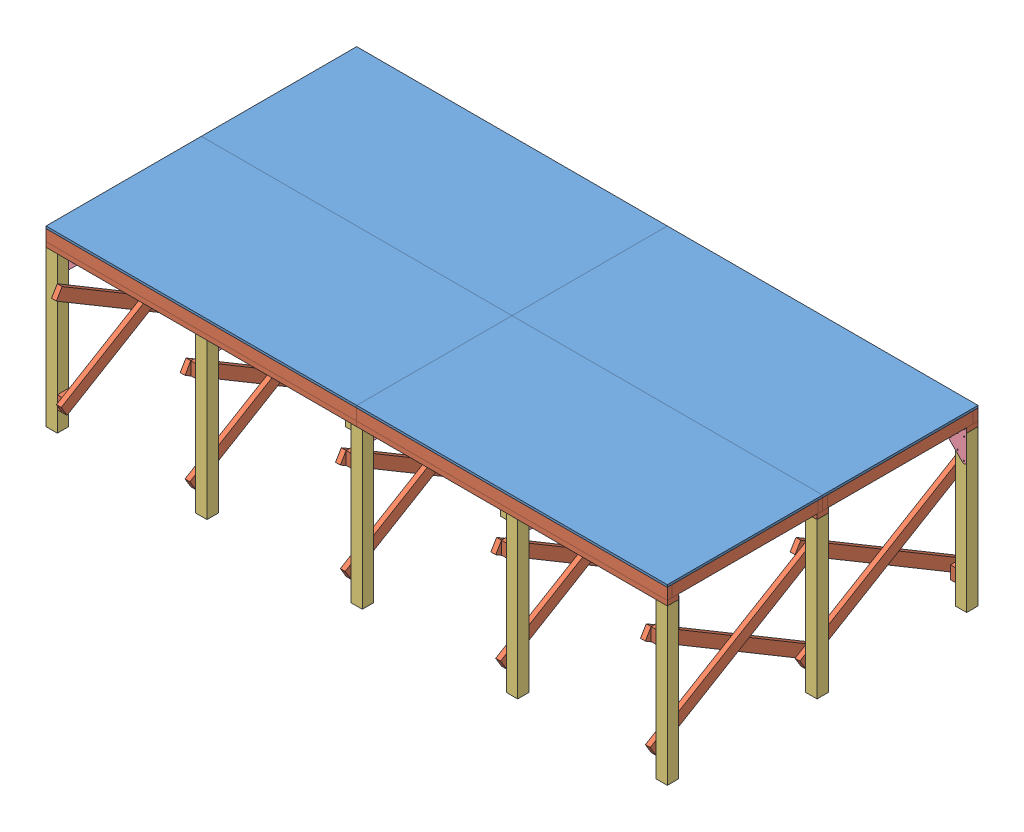
SolidWorks assembly Side Platform, configuration Default. Lengths in mm.
Overall size (5108.48 1373.14 2529.42).
113 component instances, 4 part files, 31 mates.
Components (placement in the parent):
- Platform Top-1: Platform Top [Default] at origin size (2438.4 106.76 1219.2)
  - 4x8-1: 4x8 [Default] at origin size (2438.4 17.86 1219.2)
  - 2x4 Configurable-6: 2x4 Configurable [96" Long] at (0 -53.3781 590.55) x (1 0 0) z (0 0 -1) size (2438.4 88.9 38.1)
  - 2x4 Configurable-7: 2x4 Configurable [96" Long] at (0 -53.3781 -590.55) x (1 0 0) z (0 0 -1) size (2438.4 88.9 38.1)
  - 2x4 Configurable-10: 2x4 Configurable [45" Long] at (-1200.15 -53.3781 0) x (0 0 -1) z (1 0 0) size (1143 88.9 38.1)
  - 2x4 Configurable-11: 2x4 Configurable [45" Long] at (-800.1 -53.3781 0) x (0 0 -1) z (1 0 0) size (1143 88.9 38.1)
  - 2x4 Configurable-12: 2x4 Configurable [45" Long] at (-400.05 -53.3781 0) x (0 0 -1) z (1 0 0) size (1143 88.9 38.1)
  - 2x4 Configurable-13: 2x4 Configurable [45" Long] at (0 -53.3781 0) x (0 0 -1) z (1 0 0) size (1143 88.9 38.1)
  - 2x4 Configurable-14: 2x4 Configurable [45" Long] at (400.05 -53.3781 0) x (0 0 -1) z (1 0 0) size (1143 88.9 38.1)
  - 2x4 Configurable-15: 2x4 Configurable [45" Long] at (800.1 -53.3781 0) x (0 0 -1) z (1 0 0) size (1143 88.9 38.1)
  - 2x4 Configurable-16: 2x4 Configurable [45" Long] at (1200.15 -53.3781 0) x (0 0 -1) z (1 0 0) size (1143 88.9 38.1)
- Platform Top-2: Platform Top [Default] at (-2438.4 0 0) size (2438.4 106.76 1219.2)
  - 4x8-1: 4x8 [Default] at origin size (2438.4 17.86 1219.2)
  - 2x4 Configurable-6: 2x4 Configurable [96" Long] at (0 -53.3781 590.55) x (1 0 0) z (0 0 -1) size (2438.4 88.9 38.1)
  - 2x4 Configurable-7: 2x4 Configurable [96" Long] at (0 -53.3781 -590.55) x (1 0 0) z (0 0 -1) size (2438.4 88.9 38.1)
  - 2x4 Configurable-10: 2x4 Configurable [45" Long] at (-1200.15 -53.3781 0) x (0 0 -1) z (1 0 0) size (1143 88.9 38.1)
  - 2x4 Configurable-11: 2x4 Configurable [45" Long] at (-800.1 -53.3781 0) x (0 0 -1) z (1 0 0) size (1143 88.9 38.1)
  - 2x4 Configurable-12: 2x4 Configurable [45" Long] at (-400.05 -53.3781 0) x (0 0 -1) z (1 0 0) size (1143 88.9 38.1)
  - 2x4 Configurable-13: 2x4 Configurable [45" Long] at (0 -53.3781 0) x (0 0 -1) z (1 0 0) size (1143 88.9 38.1)
  - 2x4 Configurable-14: 2x4 Configurable [45" Long] at (400.05 -53.3781 0) x (0 0 -1) z (1 0 0) size (1143 88.9 38.1)
  - 2x4 Configurable-15: 2x4 Configurable [45" Long] at (800.1 -53.3781 0) x (0 0 -1) z (1 0 0) size (1143 88.9 38.1)
  - 2x4 Configurable-16: 2x4 Configurable [45" Long] at (1200.15 -53.3781 0) x (0 0 -1) z (1 0 0) size (1143 88.9 38.1)
- Platform Top-4: Platform Top [Default] at (0 0 1219.2) size (2438.4 106.76 1219.2)
  - 4x8-1: 4x8 [Default] at origin size (2438.4 17.86 1219.2)
  - 2x4 Configurable-6: 2x4 Configurable [96" Long] at (0 -53.3781 590.55) x (1 0 0) z (0 0 -1) size (2438.4 88.9 38.1)
  - 2x4 Configurable-7: 2x4 Configurable [96" Long] at (0 -53.3781 -590.55) x (1 0 0) z (0 0 -1) size (2438.4 88.9 38.1)
  - 2x4 Configurable-10: 2x4 Configurable [45" Long] at (-1200.15 -53.3781 0) x (0 0 -1) z (1 0 0) size (1143 88.9 38.1)
  - 2x4 Configurable-11: 2x4 Configurable [45" Long] at (-800.1 -53.3781 0) x (0 0 -1) z (1 0 0) size (1143 88.9 38.1)
  - 2x4 Configurable-12: 2x4 Configurable [45" Long] at (-400.05 -53.3781 0) x (0 0 -1) z (1 0 0) size (1143 88.9 38.1)
  - 2x4 Configurable-13: 2x4 Configurable [45" Long] at (0 -53.3781 0) x (0 0 -1) z (1 0 0) size (1143 88.9 38.1)
  - 2x4 Configurable-14: 2x4 Configurable [45" Long] at (400.05 -53.3781 0) x (0 0 -1) z (1 0 0) size (1143 88.9 38.1)
  - 2x4 Configurable-15: 2x4 Configurable [45" Long] at (800.1 -53.3781 0) x (0 0 -1) z (1 0 0) size (1143 88.9 38.1)
  - 2x4 Configurable-16: 2x4 Configurable [45" Long] at (1200.15 -53.3781 0) x (0 0 -1) z (1 0 0) size (1143 88.9 38.1)
- Platform Top-5: Platform Top [Default] at (-2438.4 0 1219.2) size (2438.4 106.76 1219.2)
  - 4x8-1: 4x8 [Default] at origin size (2438.4 17.86 1219.2)
  - 2x4 Configurable-6: 2x4 Configurable [96" Long] at (0 -53.3781 590.55) x (1 0 0) z (0 0 -1) size (2438.4 88.9 38.1)
  - 2x4 Configurable-7: 2x4 Configurable [96" Long] at (0 -53.3781 -590.55) x (1 0 0) z (0 0 -1) size (2438.4 88.9 38.1)
  - 2x4 Configurable-10: 2x4 Configurable [45" Long] at (-1200.15 -53.3781 0) x (0 0 -1) z (1 0 0) size (1143 88.9 38.1)
  - 2x4 Configurable-11: 2x4 Configurable [45" Long] at (-800.1 -53.3781 0) x (0 0 -1) z (1 0 0) size (1143 88.9 38.1)
  - 2x4 Configurable-12: 2x4 Configurable [45" Long] at (-400.05 -53.3781 0) x (0 0 -1) z (1 0 0) size (1143 88.9 38.1)
  - 2x4 Configurable-13: 2x4 Configurable [45" Long] at (0 -53.3781 0) x (0 0 -1) z (1 0 0) size (1143 88.9 38.1)
  - 2x4 Configurable-14: 2x4 Configurable [45" Long] at (400.05 -53.3781 0) x (0 0 -1) z (1 0 0) size (1143 88.9 38.1)
  - 2x4 Configurable-15: 2x4 Configurable [45" Long] at (800.1 -53.3781 0) x (0 0 -1) z (1 0 0) size (1143 88.9 38.1)
  - 2x4 Configurable-16: 2x4 Configurable [45" Long] at (1200.15 -53.3781 0) x (0 0 -1) z (1 0 0) size (1143 88.9 38.1)
- Stringer Config-1: Stringer Config [2 Wide 4 ft High] at (1510.4642 -1326.0215 2262.6735) x (-1 0 0) z (0 0 -1) size (5108.48 1373.14 90.54)
  - 4x4 Configurable-1: 4x4 Configurable [48" Length] at (380.1642 -29.1066 522.7735) size (88.9 1219.2 88.9)
  - 2x4 Configurable-1: 2x4 Configurable [96" Long] at (1510.4642 1209.1434 478.3235) x (1 0 0) z (0 -1 0) size (2438.4 88.9 38.1)
  - 4x4 Configurable-2: 4x4 Configurable [48" Length] at (5168.0642 -29.1066 522.7735) size (88.9 1219.2 88.9)
  - Bracket-1: Bracket [Default] at (572.205 1228.1934 524.4153) x (0.707107 0.707107 0) z (0 0 -1) size (343.43 190.77 1.64)
  - Bracket-2: Bracket [Default] at (4887.1234 1228.1934 522.7735) x (-0.707107 0.707107 0) z (0 0 1) size (343.43 190.77 1.64)
  - 4x4 Configurable-4: 4x4 Configurable [48" Length] at (1466.0142 -29.1066 522.7735) x (0 0 1) z (-1 0 0) size (88.9 1219.2 88.9)
  - Bracket-3: Bracket [Default] at (1311.6697 1228.1934 524.4153) x (-1 0 0) z (0 0 -1) size (343.43 190.77 1.64)
  - 2x4 Configurable-4: 2x4 Configurable [96" Long] at (3948.8642 1209.1434 478.3235) x (1 0 0) z (0 -1 0) size (2438.4 88.9 38.1)
  - Bracket-9: Bracket [Default] at (2530.8697 1228.1934 524.4153) x (-1 0 0) z (0 0 -1) size (343.43 190.77 1.64)
  - Bracket-10: Bracket [Default] at (3750.0697 1228.1934 524.4153) x (-1 0 0) z (0 0 -1) size (343.43 190.77 1.64)
  - 4x4 Configurable-10: 4x4 Configurable [48" Length] at (2685.2142 -29.1066 522.7735) x (0 0 1) z (-1 0 0) size (88.9 1219.2 88.9)
  - 4x4 Configurable-11: 4x4 Configurable [48" Length] at (3904.4142 -29.1066 522.7735) x (0 0 1) z (-1 0 0) size (88.9 1219.2 88.9)
- Stringer Config-6: Stringer Config [2 Wide 4 ft High] at (1510.4642 -1326.0215 1087.9235) x (-1 0 0) z (0 0 -1) size (5108.48 1373.14 90.54)
  - 4x4 Configurable-1: 4x4 Configurable [48" Length] at (380.1642 -29.1066 522.7735) size (88.9 1219.2 88.9)
  - 2x4 Configurable-1: 2x4 Configurable [96" Long] at (1510.4642 1209.1434 478.3235) x (1 0 0) z (0 -1 0) size (2438.4 88.9 38.1)
  - 4x4 Configurable-2: 4x4 Configurable [48" Length] at (5168.0642 -29.1066 522.7735) size (88.9 1219.2 88.9)
  - Bracket-1: Bracket [Default] at (572.205 1228.1934 524.4153) x (0.707107 0.707107 0) z (0 0 -1) size (343.43 190.77 1.64)
  - Bracket-2: Bracket [Default] at (4887.1234 1228.1934 522.7735) x (-0.707107 0.707107 0) z (0 0 1) size (343.43 190.77 1.64)
  - 4x4 Configurable-4: 4x4 Configurable [48" Length] at (1466.0142 -29.1066 522.7735) x (0 0 1) z (-1 0 0) size (88.9 1219.2 88.9)
  - Bracket-3: Bracket [Default] at (1311.6697 1228.1934 524.4153) x (-1 0 0) z (0 0 -1) size (343.43 190.77 1.64)
  - 2x4 Configurable-4: 2x4 Configurable [96" Long] at (3948.8642 1209.1434 478.3235) x (1 0 0) z (0 -1 0) size (2438.4 88.9 38.1)
  - Bracket-9: Bracket [Default] at (2530.8697 1228.1934 524.4153) x (-1 0 0) z (0 0 -1) size (343.43 190.77 1.64)
  - Bracket-10: Bracket [Default] at (3750.0697 1228.1934 524.4153) x (-1 0 0) z (0 0 -1) size (343.43 190.77 1.64)
  - 4x4 Configurable-10: 4x4 Configurable [48" Length] at (2685.2142 -29.1066 522.7735) x (0 0 1) z (-1 0 0) size (88.9 1219.2 88.9)
  - 4x4 Configurable-11: 4x4 Configurable [48" Length] at (3904.4142 -29.1066 522.7735) x (0 0 1) z (-1 0 0) size (88.9 1219.2 88.9)
- Stringer Config-7: Stringer Config [2 Wide 4 ft High] at (-3948.8642 -1326.0215 -1043.4735) size (5108.48 1373.14 90.54)
  - 4x4 Configurable-1: 4x4 Configurable [48" Length] at (380.1642 -29.1066 522.7735) size (88.9 1219.2 88.9)
  - 2x4 Configurable-1: 2x4 Configurable [96" Long] at (1510.4642 1209.1434 478.3235) x (1 0 0) z (0 -1 0) size (2438.4 88.9 38.1)
  - 4x4 Configurable-2: 4x4 Configurable [48" Length] at (5168.0642 -29.1066 522.7735) size (88.9 1219.2 88.9)
  - Bracket-1: Bracket [Default] at (572.205 1228.1934 524.4153) x (0.707107 0.707107 0) z (0 0 -1) size (343.43 190.77 1.64)
  - Bracket-2: Bracket [Default] at (4887.1234 1228.1934 522.7735) x (-0.707107 0.707107 0) z (0 0 1) size (343.43 190.77 1.64)
  - 4x4 Configurable-4: 4x4 Configurable [48" Length] at (1466.0142 -29.1066 522.7735) x (0 0 1) z (-1 0 0) size (88.9 1219.2 88.9)
  - Bracket-3: Bracket [Default] at (1311.6697 1228.1934 524.4153) x (-1 0 0) z (0 0 -1) size (343.43 190.77 1.64)
  - 2x4 Configurable-4: 2x4 Configurable [96" Long] at (3948.8642 1209.1434 478.3235) x (1 0 0) z (0 -1 0) size (2438.4 88.9 38.1)
  - Bracket-9: Bracket [Default] at (2530.8697 1228.1934 524.4153) x (-1 0 0) z (0 0 -1) size (343.43 190.77 1.64)
  - Bracket-10: Bracket [Default] at (3750.0697 1228.1934 524.4153) x (-1 0 0) z (0 0 -1) size (343.43 190.77 1.64)
  - 4x4 Configurable-10: 4x4 Configurable [48" Length] at (2685.2142 -29.1066 522.7735) x (0 0 1) z (-1 0 0) size (88.9 1219.2 88.9)
  - 4x4 Configurable-11: 4x4 Configurable [48" Length] at (3904.4142 -29.1066 522.7735) x (0 0 1) z (-1 0 0) size (88.9 1219.2 88.9)
- 2x4 Configurable-1: 2x4 Configurable [60" Long] at (1111.25 -767.4002 1196.975) x (0 -0.511927 0.859029) z (-1 0 0) size (1524 88.9 38.1)
- 2x4 Configurable-9: 2x4 Configurable [60" Long] at (1073.15 -767.4002 1196.975) x (0 0.511927 0.859029) z (-1 0 0) size (1524 88.9 38.1)
- 2x4 Configurable-10: 2x4 Configurable [60" Long] at (-63.5 -767.4002 1196.975) x (0 -0.511927 0.859029) z (-1 0 0) size (1524 88.9 38.1)
- 2x4 Configurable-11: 2x4 Configurable [60" Long] at (1111.25 -767.4002 22.225) x (0 -0.511927 0.859029) z (-1 0 0) size (1524 88.9 38.1)
- 2x4 Configurable-12: 2x4 Configurable [60" Long] at (-63.5 -767.4002 22.225) x (0 -0.511927 0.859029) z (-1 0 0) size (1524 88.9 38.1)
- 2x4 Configurable-13: 2x4 Configurable [60" Long] at (-101.6 -767.4002 1196.975) x (0 0.511927 0.859029) z (-1 0 0) size (1524 88.9 38.1)
- 2x4 Configurable-14: 2x4 Configurable [60" Long] at (1073.15 -767.4002 22.225) x (0 0.511927 0.859029) z (-1 0 0) size (1524 88.9 38.1)
- 2x4 Configurable-15: 2x4 Configurable [60" Long] at (-101.6 -767.4002 22.225) x (0 0.511927 0.859029) z (-1 0 0) size (1524 88.9 38.1)
- 2x4 Configurable-32: 2x4 Configurable [60" Long] at (-1320.8 -767.4002 22.225) x (0 0.511927 0.859029) z (-1 0 0) size (1524 88.9 38.1)
- 2x4 Configurable-33: 2x4 Configurable [60" Long] at (-2540 -767.4002 22.225) x (0 0.511927 0.859029) z (-1 0 0) size (1524 88.9 38.1)
- 2x4 Configurable-34: 2x4 Configurable [60" Long] at (-1282.7 -767.4002 22.225) x (0 -0.511927 0.859029) z (-1 0 0) size (1524 88.9 38.1)
- 2x4 Configurable-35: 2x4 Configurable [60" Long] at (-2501.9 -767.4002 22.225) x (0 -0.511927 0.859029) z (-1 0 0) size (1524 88.9 38.1)
- 2x4 Configurable-36: 2x4 Configurable [60" Long] at (-1282.7 -767.4002 1196.975) x (0 -0.511927 0.859029) z (-1 0 0) size (1524 88.9 38.1)
- 2x4 Configurable-37: 2x4 Configurable [60" Long] at (-2501.9 -767.4002 1196.975) x (0 -0.511927 0.859029) z (-1 0 0) size (1524 88.9 38.1)
- 2x4 Configurable-38: 2x4 Configurable [60" Long] at (-1320.8 -767.4002 1196.975) x (0 0.511927 0.859029) z (-1 0 0) size (1524 88.9 38.1)
- 2x4 Configurable-39: 2x4 Configurable [60" Long] at (-2540 -767.4002 1196.975) x (0 0.511927 0.859029) z (-1 0 0) size (1524 88.9 38.1)
- 2x4 Configurable-40: 2x4 Configurable [60" Long] at (-3511.55 -767.4002 1196.975) x (0 -0.511927 0.859029) z (-1 0 0) size (1524 88.9 38.1)
- 2x4 Configurable-41: 2x4 Configurable [60" Long] at (-3549.65 -767.4002 1196.975) x (0 0.511927 0.859029) z (-1 0 0) size (1524 88.9 38.1)
- 2x4 Configurable-42: 2x4 Configurable [60" Long] at (-3511.55 -767.4002 22.225) x (0 -0.511927 0.859029) z (-1 0 0) size (1524 88.9 38.1)
- 2x4 Configurable-43: 2x4 Configurable [60" Long] at (-3549.65 -767.4002 22.225) x (0 0.511927 0.859029) z (-1 0 0) size (1524 88.9 38.1)
- 2x4 Configurable-44: 2x4 Configurable [4" Long] at (1111.25 -389.9281 1784.35) x (0 -1 0) z (1 0 0) size (101.6 88.9 38.1)
- 2x4 Configurable-45: 2x4 Configurable [4" Long] at (1111.25 -1144.8723 -565.15) x (0 -1 0) z (1 0 0) size (101.6 88.9 38.1)
- 2x4 Configurable-46: 2x4 Configurable [4" Long] at (-63.5 -389.9281 1784.35) x (0 -1 0) z (1 0 0) size (101.6 88.9 38.1)
- 2x4 Configurable-47: 2x4 Configurable [4" Long] at (-63.5 -1144.8723 -565.15) x (0 -1 0) z (1 0 0) size (101.6 88.9 38.1)
- 2x4 Configurable-58: 2x4 Configurable [4" Long] at (-1282.7 -389.9281 1784.35) x (0 -1 0) z (1 0 0) size (101.6 88.9 38.1)
- 2x4 Configurable-59: 2x4 Configurable [4" Long] at (-2501.9 -389.9281 1784.35) x (0 -1 0) z (1 0 0) size (101.6 88.9 38.1)
- 2x4 Configurable-60: 2x4 Configurable [4" Long] at (-1282.7 -1144.8723 -565.15) x (0 -1 0) z (1 0 0) size (101.6 88.9 38.1)
- 2x4 Configurable-61: 2x4 Configurable [4" Long] at (-2501.9 -1144.8723 -565.15) x (0 -1 0) z (1 0 0) size (101.6 88.9 38.1)
- 2x4 Configurable-64: 2x4 Configurable [4" Long] at (-3549.65 -389.9281 -565.15) x (0 -1 0) z (1 0 0) size (101.6 88.9 38.1)
- 2x4 Configurable-65: 2x4 Configurable [4" Long] at (-3549.65 -1144.8723 1784.35) x (0 -1 0) z (1 0 0) size (101.6 88.9 38.1)
Mates (geometry in assembly coordinates):
- Coincident1: coincident anti-aligned: line of Platform-13/2x4 Configurable-6 through (1219.2 -97.8281 5486.4) axis (0 0 -1); line of Stringer Config-1/2x4 Configurable-1 through (1219.2 -97.8281 1739.9) axis (0 0 1)
- Coincident2: coincident aligned: line of Platform-13/2x4 Configurable-6 through (1219.2 -97.8281 5486.4) axis (-1 0 0); line of Stringer Config-1/2x4 Configurable-1 through (1219.2 -97.8281 1828.8) axis (-1 0 0)
- Coincident6: coincident anti-aligned: plane of Platform-4/2x4 Configurable-6 through (-1219.2 -97.8281 1828.8) normal (0 -1 0); plane of Stringer Config-1/2x4 Configurable-1 through (0 -97.8281 1784.35) normal (0 1 0)
- Coincident7: coincident aligned: line of Platform-4/2x4 Configurable-6 through (1219.2 -8.9281 1828.8) axis (0 -1 0); line of Stringer Config-1/4x4 Configurable-1 through (1219.2 -135.9281 1828.8) axis (0 -1 0)
- Coincident8: coincident anti-aligned: line of Platform-4/2x4 Configurable-16 through (1219.2 -97.8281 1790.7) axis (0 0 -1); line of Stringer Config-1/2x4 Configurable-1 through (1219.2 -97.8281 1739.9) axis (0 0 1)
- Coincident9: coincident: point of Platform-1/2x4 Configurable-6; moEndPointRef_w of Stringer Config-6/2x4 Configurable-1
- Coincident10: coincident anti-aligned: plane of Platform-5/2x4 Configurable-7 through (-3657.6 -97.8281 647.7) normal (0 -1 0); plane of Stringer Config-6/2x4 Configurable-1 through (0 -97.8281 609.6) normal (0 1 0)
- Coincident11: coincident aligned: line of Platform-2/2x4 Configurable-6 through (-3657.6 -97.8281 609.6) axis (0 0 -1); line of Stringer Config-6/2x4 Configurable-4 through (-3657.6 -97.8281 654.05) axis (0 0 -1)
- Coincident12: coincident aligned: line of Platform-1/2x4 Configurable-7 through (1219.2 -8.9281 -609.6) axis (0 -1 0); line of Stringer Config-7/2x4 Configurable-4 through (1219.2 -97.8281 -609.6) axis (0 -1 0)
- Coincident13: coincident anti-aligned: line of Platform-1/2x4 Configurable-16 through (1219.2 -97.8281 571.5) axis (0 0 -1); line of Stringer Config-7/2x4 Configurable-4 through (1219.2 -97.8281 -609.6) axis (0 0 1)
- Coincident14: coincident anti-aligned: plane of Stringer Config-1/4x4 Configurable-1 through (1130.3 -135.9281 1739.9) normal (-1 0 0); plane of 2x4 Configurable-1 through (1130.3 -767.4002 1196.975) normal (1 0 0)
- Coincident15: coincident anti-aligned: plane of Stringer Config-6/4x4 Configurable-1 through (1130.3 -135.9281 565.15) normal (-1 0 0); plane of 2x4 Configurable-1 through (1130.3 -767.4002 1196.975) normal (1 0 0)
- Coincident16: coincident: line of Stringer Config-1/4x4 Configurable-1 through (1130.3 -135.9281 1828.8) axis (0 -1 0); point of 2x4 Configurable-1
- Coincident17: coincident: line of Stringer Config-6/4x4 Configurable-1 through (1130.3 -135.9281 565.15) axis (0 -1 0); point of 2x4 Configurable-1
- Distance8: distance = 203.2 mm: point of 2x4 Configurable-1; point of Stringer Config-6/4x4 Configurable-1
- Coincident58: coincident: point of 2x4 Configurable-1; plane of 2x4 Configurable-9 through (1073.15 -767.4002 1196.975) normal (0 0.511927 0.859029)
- Coincident59: coincident: point of 2x4 Configurable-1; plane of 2x4 Configurable-9 through (1073.15 -767.4002 1196.975) normal (0 0.859029 -0.511927)
- Coincident60: coincident anti-aligned: plane of 2x4 Configurable-1 through (1092.2 -767.4002 1196.975) normal (-1 0 0); plane of 2x4 Configurable-9 through (1092.2 -767.4002 1196.975) normal (1 0 0)
- Distance20: distance = 0 mm: line of 2x4 Configurable-9 through (1092.2 -339.1281 1828.8) axis (-1 0 0); line of Stringer Config-1/4x4 Configurable-1 through (1130.3 -135.9281 1828.8) axis (0 -1 0)
- Coincident62: coincident anti-aligned: plane of Stringer Config-1/4x4 Configurable-1 through (1130.3 -135.9281 1739.9) normal (-1 0 0); plane of 2x4 Configurable-44 through (1130.3 -389.9281 1784.35) normal (1 0 0)
- Coincident63: coincident aligned: line of Stringer Config-1/4x4 Configurable-1 through (1130.3 -135.9281 1828.8) axis (0 -1 0); line of 2x4 Configurable-44 through (1130.3 -339.1281 1828.8) axis (0 -1 0)
- Coincident64: coincident: point of 2x4 Configurable-9; line of 2x4 Configurable-44 through (1092.2 -339.1281 1739.9) axis (0 0 1)
- Coincident65: coincident anti-aligned: line of Stringer Config-7/4x4 Configurable-2 through (1130.3 -135.9281 -609.6) axis (0 -1 0); line of 2x4 Configurable-45 through (1130.3 -1195.6723 -609.6) axis (0 1 0)
- Coincident66: coincident anti-aligned: plane of Stringer Config-7/4x4 Configurable-2 through (1130.3 -135.9281 -609.6) normal (-1 0 0); plane of 2x4 Configurable-45 through (1130.3 -1144.8723 -565.15) normal (1 0 0)
- Coincident69: coincident: point of 2x4 Configurable-14; point of 2x4 Configurable-45
- Coincident73: coincident anti-aligned: plane of Stringer Config-7/4x4 Configurable-1 through (-3568.7 -135.9281 -520.7) normal (1 0 0); plane of 2x4 Configurable-64 through (-3568.7 -389.9281 -565.15) normal (-1 0 0)
- Coincident74: coincident anti-aligned: line of Stringer Config-7/4x4 Configurable-1 through (-3568.7 -135.9281 -609.6) axis (0 -1 0); line of 2x4 Configurable-64 through (-3568.7 -440.7281 -609.6) axis (0 1 0)
- Coincident78: coincident: line of 2x4 Configurable-64 through (-3530.6 -339.1281 -609.6) axis (0 0 1); point of 2x4 Configurable-42
- Coincident79: coincident anti-aligned: plane of Stringer Config-1/4x4 Configurable-2 through (-3568.7 -135.9281 1828.8) normal (1 0 0); plane of 2x4 Configurable-65 through (-3568.7 -1144.8723 1784.35) normal (-1 0 0)
- Coincident80: coincident aligned: line of Stringer Config-1/4x4 Configurable-2 through (-3568.7 -135.9281 1828.8) axis (0 -1 0); line of 2x4 Configurable-65 through (-3568.7 -1094.0723 1828.8) axis (0 -1 0)
- Coincident82: coincident: point of 2x4 Configurable-40; line of 2x4 Configurable-65 through (-3530.6 -1195.6723 1828.8) axis (0 0 -1)
